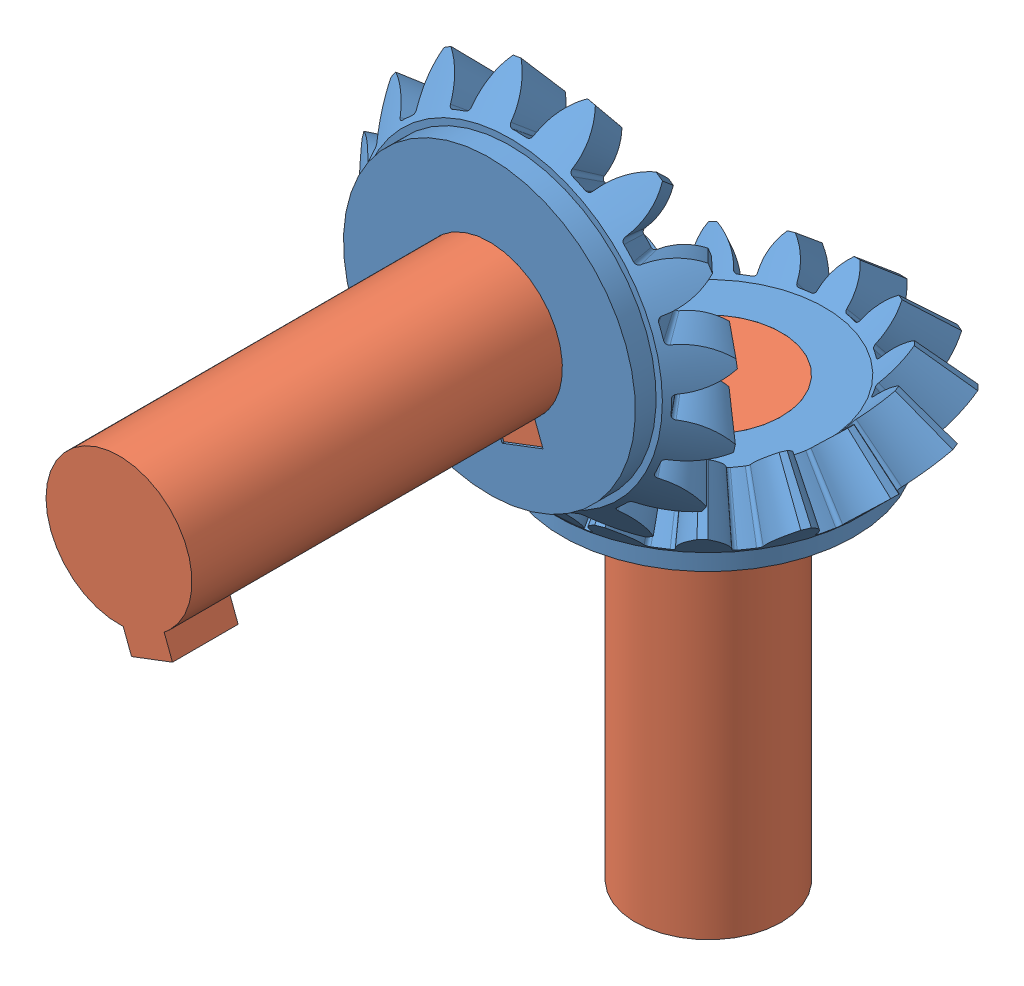
SolidWorks assembly gears, configuration Default. Lengths in mm.
Overall size (66.96 114.23 111.71).
4 component instances, 2 part files, 12 mates.
Components (placement in the parent):
- Perfect bevel-1: Perfect bevel [Metric - Straight bevel pinion 3M16PT 16GT 20PA 8FW ---16O40H30MD20S1] at (0 0 -2.8491) x (0 0 -1) z (-0.934874 -0.354981 0) size (13.66 51.91 51.91)
- Perfect bevel-2: Perfect bevel [Metric - Straight bevel pinion 3M16PT 16GT 20PA 8FW ---16O40H30MD20S1] at (0 -27.151 -30.0001) x (0 1 0) z (-0.216364 0 0.976313) size (13.66 51.91 51.91)
- 20 D shaft-1: 20 D shaft [Default] at (0 0 20.7514) x (0.934874 0.354981 0) z (0 0 -1) size (20 22.75 60)
- 20 D shaft-2: 20 D shaft [Default] at (0 -50.7515 -30.0001) x (0.216364 0 -0.976313) z (0 1 0) size (20 22.75 60)
Mates (geometry in assembly coordinates):
- Coincident19: coincident aligned: plane of straight bevel pinion_am-1 through (0 0 0) normal (0 0 1)
- Concentric5: concentric: cylinder of straight bevel pinion_am-1 through (0 0 -32.8491) axis (0 0 1) radius 10
- Coincident21: coincident: point of Perfect bevel-1; point of Perfect bevel-2
- Perpendicular3: perpendicular: line of straight bevel pinion_am-1 through (0 0 7.1509) axis (0 0 -1); line of straight bevel pinion_am-2 through (0 -37.151 -30.0001) axis (0 1 0)
- Parallel7: parallel anti-aligned: plane of straight bevel pinion_am-2 through (0 -30.0001 -30.0001) normal (0 -1 0)
- GearMate3: gear = 20 : 20 mm: cylinder of straight bevel pinion_am-2 through (0 2.849 -30.0001) axis (0 -1 0) radius 10; cylinder of straight bevel pinion_am-1 through (0 0 -32.8491) axis (0 0 1) radius 10
- Concentric7: concentric aligned: cylinder of Perfect bevel-1 through (0 0 -32.8491) axis (0 0 1) radius 10; cylinder of 20 D shaft-1 through (0 0 -9.2486) axis (0 0 1) radius 10
- Coincident24: coincident aligned: plane of Perfect bevel-1 through (0 0 -9.2486) normal (0 0 -1); plane of 20 D shaft-1 through (0 0 -9.2486) normal (0 0 -1)
- Coincident25: coincident anti-aligned: plane of Perfect bevel-1 through (7.3484 -10.9014 -32.8491) normal (-0.934874 -0.354981 0); plane of 20 D shaft-1 through (7.3289 -10.85 -0.2486) normal (0.934874 0.354981 0)
- Concentric8: concentric aligned: cylinder of Perfect bevel-2 through (0 2.849 -30.0001) axis (0 -1 0) radius 10; cylinder of 20 D shaft-2 through (0 -20.7515 -30.0001) axis (0 -1 0) radius 10
- Coincident26: coincident aligned: plane of Perfect bevel-2 through (0 -20.7515 -30.0001) normal (0 1 0); plane of 20 D shaft-2 through (0 -20.7515 -30.0001) normal (0 1 0)
- Coincident28: coincident anti-aligned: plane of Perfect bevel-2 through (-0.6491 2.849 -27.0712) normal (0.216364 0 -0.976313); plane of 20 D shaft-2 through (-13.0922 -29.7515 -29.8287) normal (-0.216364 0 0.976313)
